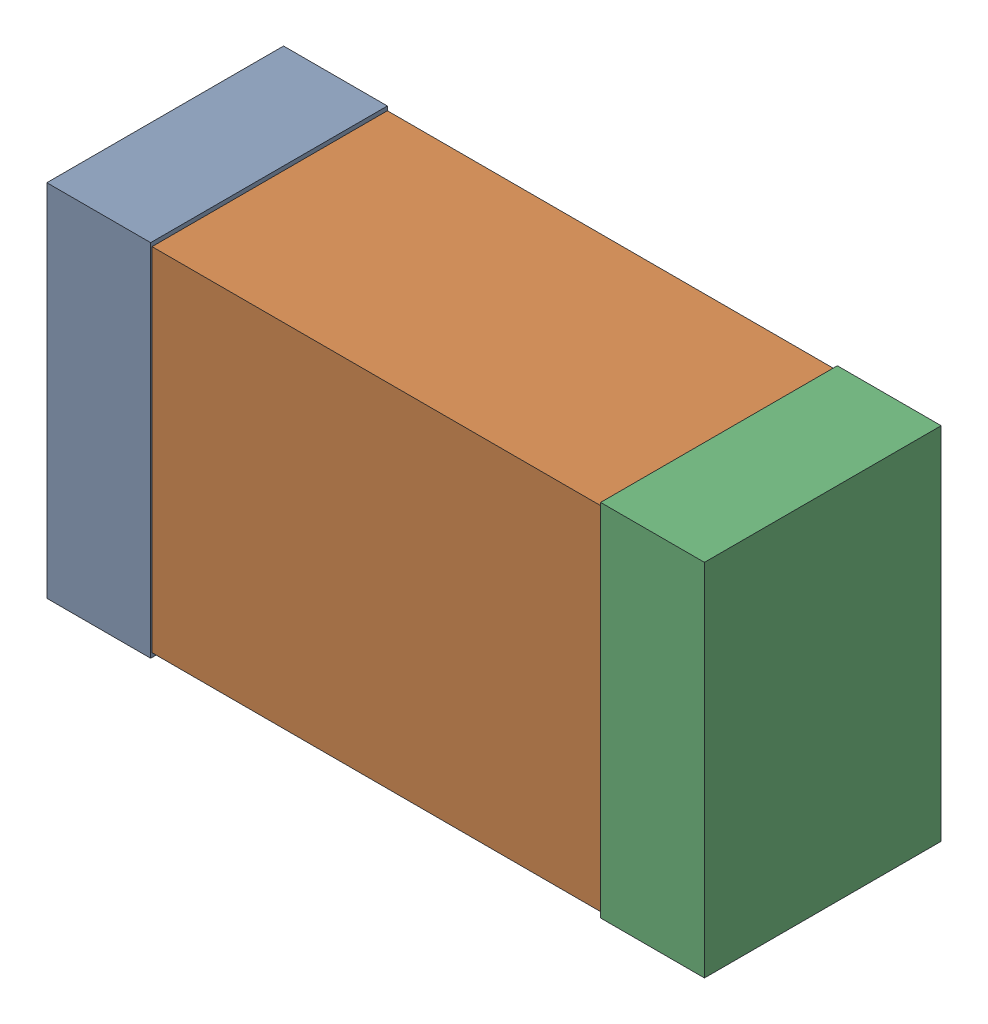
SolidWorks assembly CSS12Kanaloa_v2.0.0_Power, configuration Default. Lengths in mm.
Overall size (2.38 1.3 0.85).
6 component instances, 2 part files, 0 mates.
Components (placement in the parent):
- 352877648-1: 352877648 [Default] at (43.45 128.016 0) size (0.38 1.3 0.85)
  - Extruded_14-1: Extruded_14 [Default] at origin size (0.38 1.3 0.85)
- 352877392-1: 352877392 [Default] at (44.45 128.016 0) size (2.2 1.27 0.85)
  - Extruded_15-1: Extruded_15 [Default] at origin size (2.2 1.27 0.85)
- 352877648-2: 352877648 [Default] at (45.45 128.016 0) size (0.38 1.3 0.85)
  - Extruded_14-1: Extruded_14 [Default] at origin size (0.38 1.3 0.85)
